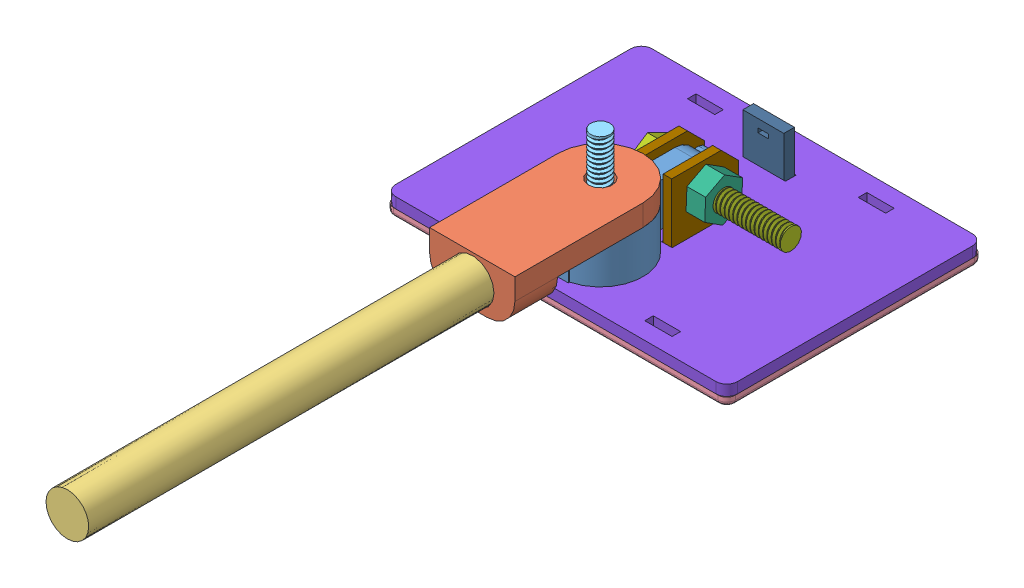
SolidWorks assembly Pet Brush Assembly, configuration Default. Lengths in mm.
Overall size (101.6 32.44 221.74).
12 component instances, 10 part files, 30 mates.
Components (placement in the parent):
- HorizVertLinkage-1: HorizVertLinkage [Default] at (-28.6504 9.525 -2.1287) x (-1 0 0) z (0 0 -1) size (25.4 12.7 47.62)
- HorizPivot3-1: HorizPivot3 [Default] at (-28.6504 15.875 23.2713) x (-1 0 0) z (0 0 -1) size (25.4 14.61 50.8)
- handle-1: handle [Default] at (-28.6504 14.9225 181.7673) x (0.85418 -0.519977 0) z (0 0 -1) size (12.7 12.7 127)
- BristlesV2-1: BristlesV2 [Default] at (-28.9044 -4.445 36.2253) x (1 0 0) z (0 0 -1) size (101.6 5.62 76.2)
- Bolt_1in-1: Bolt_1in [Default] at (-28.6504 5.3848 23.2713) x (0.797835 0 0.602876) z (0 1 0) size (12.83 11.11 29.54) (hidden)
- Nut-1: Nut [Default] at (-17.3728 9.525 -2.1287) x (0 -0.463458 0.886119) z (-1 0 0) size (12.7 11 5.56) (hidden)
- Nut-2: Nut [Default] at (-28.6504 22.225 23.2713) x (0.989571 0 0.144044) z (0 1 0) size (12.7 11 5.56) (hidden)
- Bolt_1.5In-1: Bolt_1.5In [Default] at (-39.6486 9.525 -2.1287) x (0 0.550438 -0.834876) z (1 0 0) size (12.83 11.11 42.24) (hidden)
- BristleHolderLaserCut-1: BristleHolderLaserCut [Default] at (-28.9044 -3.175 -1.8747) size (101.6 3.17 76.2)
- VertSupportLaserCut-1: VertSupportLaserCut [Default] at (-32.9684 -3.175 -12.0347) x (0 0 1) z (-1 0 0) size (19.81 20.32 2.54)
- VertSupportLaserCut-2: VertSupportLaserCut [Default] at (-22.9354 -3.175 -12.0347) x (0 0 1) z (-1 0 0) size (19.81 20.32 2.54)
- Spring Holder-1: Spring Holder [Default] at (-35.2544 -3.175 -28.8749) size (12.19 15.24 3.17)
Mates (geometry in assembly coordinates):
- Concentric2: concentric aligned: cylinder of HorizVertLinkage-1 through (-28.6504 15.876 23.2713) axis (0 -1 0) radius 3.556; cylinder of HorizPivot3-1 through (-28.6504 22.225 23.2713) axis (0 -1 0) radius 3.556
- Coincident3: coincident anti-aligned: plane of HorizVertLinkage-1 through (-31.8254 15.875 -2.1287) normal (0 1 0); plane of HorizPivot3-1 through (-28.6504 15.875 23.2713) normal (0 -1 0)
- Concentric5: concentric aligned: cylinder of HorizPivot3-1 through (-28.6504 22.225 23.2713) axis (0 -1 0) radius 3.556; cylinder of Bolt_1in-1 through (-28.6504 34.925 23.2713) axis (0 -1 0) radius 2.901
- Concentric6: concentric aligned: cylinder of Bolt_1in-1 through (-28.6504 34.925 23.2713) axis (0 -1 0) radius 2.901; cylinder of Nut-2 through (-28.6504 27.7876 23.2713) axis (0 -1 0) radius 3.175
- Coincident10: coincident anti-aligned: plane of HorizPivot3-1 through (-28.6504 22.225 23.2713) normal (0 1 0); plane of Nut-2 through (-28.6504 22.225 23.2713) normal (0 -1 0)
- Coincident11: coincident anti-aligned: plane of HorizVertLinkage-1 through (-28.6504 9.525 23.2713) normal (0 -1 0); plane of Bolt_1in-1 through (-28.6504 9.525 23.2713) normal (0 1 0)
- Concentric8: concentric anti-aligned: cylinder of Nut-1 through (-22.9354 9.525 -2.1287) axis (1 0 0) radius 3.175; cylinder of Bolt_1.5In-1 through (2.5916 9.525 -2.1287) axis (-1 0 0) radius 3.175
- Coincident24: coincident anti-aligned: plane of HorizPivot3-1 through (-28.6504 14.9225 54.7673) normal (0 0 1); plane of handle-1 through (-28.6504 14.9225 54.7673) normal (0 0 -1)
- Concentric9: concentric aligned: cylinder of HorizPivot3-1 through (-28.6504 14.9225 54.7673) axis (0 0 1) radius 6.477; cylinder of handle-1 through (-28.6504 14.9225 54.7673) axis (0 0 1) radius 6.35
- Coincident25: coincident anti-aligned: plane of brush final-1 through (-79.7044 -3.175 -39.9747) normal (0 1 0); plane of BristleHolderLaserCut-1 through (-28.9044 -3.175 -1.8747) normal (0 -1 0)
- Coincident26: coincident aligned: plane of brush final-1 through (-58.3684 -5.715 -32.3547) normal (0 0 -1); plane of BristleHolderLaserCut-1 through (-58.3684 0 -32.3547) normal (0 0 -1)
- Coincident27: coincident aligned: plane of brush final-1 through (-58.3684 -5.715 -34.8947) normal (1 0 0); plane of BristleHolderLaserCut-1 through (-58.3684 0 -32.3547) normal (1 0 0)
- Coincident28: coincident anti-aligned: plane of BristleHolderLaserCut-1 through (-35.5084 -3.175 8.2853) normal (1 0 0); plane of VertSupportLaserCut-1 through (-35.5084 -3.175 -12.0347) normal (-1 0 0)
- Coincident29: coincident anti-aligned: plane of BristleHolderLaserCut-1 through (-35.5084 -3.175 -12.0347) normal (0 0 1); plane of VertSupportLaserCut-1 through (-35.5084 -3.175 -12.0347) normal (0 0 -1)
- Coincident30: coincident aligned: plane of BristleHolderLaserCut-1 through (-28.9044 -3.175 -1.8747) normal (0 -1 0); plane of VertSupportLaserCut-1 through (-35.5084 -3.175 -12.0347) normal (0 -1 0)
- Coincident31: coincident anti-aligned: plane of BristleHolderLaserCut-1 through (-25.4754 -3.175 8.2853) normal (1 0 0); plane of VertSupportLaserCut-2 through (-25.4754 -3.175 -12.0347) normal (-1 0 0)
- Coincident32: coincident anti-aligned: plane of BristleHolderLaserCut-1 through (-22.3004 -3.175 -12.0347) normal (0 0 1); plane of VertSupportLaserCut-2 through (-25.4754 -3.175 -12.0347) normal (0 0 -1)
- Coincident33: coincident aligned: plane of BristleHolderLaserCut-1 through (-28.9044 -3.175 -1.8747) normal (0 -1 0); plane of VertSupportLaserCut-2 through (-25.4754 -3.175 -12.0347) normal (0 -1 0)
- Concentric10: concentric anti-aligned: cylinder of Bolt_1.5In-1 through (2.5916 9.525 -2.1287) axis (-1 0 0) radius 3.175; cylinder of VertSupportLaserCut-1 through (-35.5084 9.525 -2.1287) axis (1 0 0) radius 3.302
- Coincident34: coincident anti-aligned: plane of HorizVertLinkage-1 through (-25.4754 9.525 -2.1287) normal (1 0 0); plane of VertSupportLaserCut-2 through (-25.4754 -3.175 -12.0347) normal (-1 0 0)
- Concentric11: concentric anti-aligned: cylinder of HorizVertLinkage-1 through (-31.8254 9.525 -2.1287) axis (1 0 0) radius 3.302; cylinder of Bolt_1.5In-1 through (2.5916 9.525 -2.1287) axis (-1 0 0) radius 3.175
- Coincident35: coincident anti-aligned: plane of Bolt_1.5In-1 through (-35.5084 9.525 -2.1287) normal (1 0 0); plane of VertSupportLaserCut-1 through (-35.5084 -3.175 -12.0347) normal (-1 0 0)
- Coincident36: coincident anti-aligned: plane of Nut-1 through (-22.9354 9.525 -2.1287) normal (-1 0 0); plane of VertSupportLaserCut-2 through (-22.9354 -3.175 -12.0347) normal (1 0 0)
- Coincident37: coincident aligned: plane of BristleHolderLaserCut-1 through (-28.9044 0 -1.8747) normal (0 1 0)
- Parallel1: parallel anti-aligned: plane of BristleHolderLaserCut-1 through (-79.7044 0 36.2253) normal (-1 0 0)
- Coincident38: coincident anti-aligned: plane of BristleHolderLaserCut-1 through (-35.2544 -3.175 -28.8749) normal (0 0 1); plane of Spring Holder-1 through (-35.2544 -3.175 -28.8749) normal (0 0 -1)
- Coincident39: coincident anti-aligned: plane of BristleHolderLaserCut-1 through (-35.2544 -3.175 -28.8749) normal (1 0 0); plane of Spring Holder-1 through (-35.2544 -3.175 -25.6999) normal (-1 0 0)
- Coincident40: coincident aligned: plane of BristleHolderLaserCut-1 through (-28.9044 -3.175 -1.8747) normal (0 -1 0); plane of Spring Holder-1 through (-35.2544 -3.175 -25.6999) normal (0 -1 0)
- Parallel2: parallel aligned: plane of HorizPivot3-1 through (-28.6504 22.225 23.2713) normal (0 1 0); plane of BristleHolderLaserCut-1 through (-28.9044 0 -1.8747) normal (0 1 0)
- Parallel3: parallel aligned: plane of HorizPivot3-1 through (-15.9504 22.225 23.2713) normal (1 0 0); plane of BristleHolderLaserCut-1 through (21.8956 0 36.2253) normal (1 0 0)
